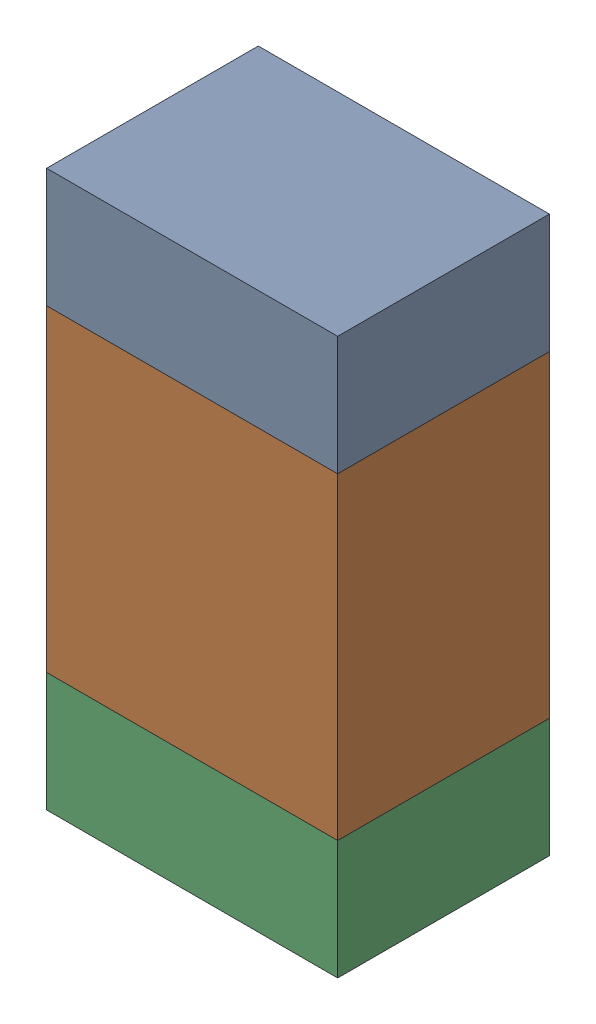
SolidWorks assembly R312_2PCB, configuration Default. Lengths in mm.
Overall size (0.55 1.05 0.4).
6 component instances, 2 part files, 0 mates.
Components (placement in the parent):
- 846483288-1: 846483288 [Default] at (125.0001 93.7126 -2.0638) size (0.55 0.22 0.4)
  - Extruded_12-1: Extruded_12 [Default] at origin size (0.55 0.22 0.4)
- 846483424-1: 846483424 [Default] at (125.0001 93.3001 -2.0638) size (0.55 0.6 0.4)
  - Extruded_13-1: Extruded_13 [Default] at origin size (0.55 0.6 0.4)
- 846483288-2: 846483288 [Default] at (125.0001 92.8876 -2.0638) size (0.55 0.22 0.4)
  - Extruded_12-1: Extruded_12 [Default] at origin size (0.55 0.22 0.4)
